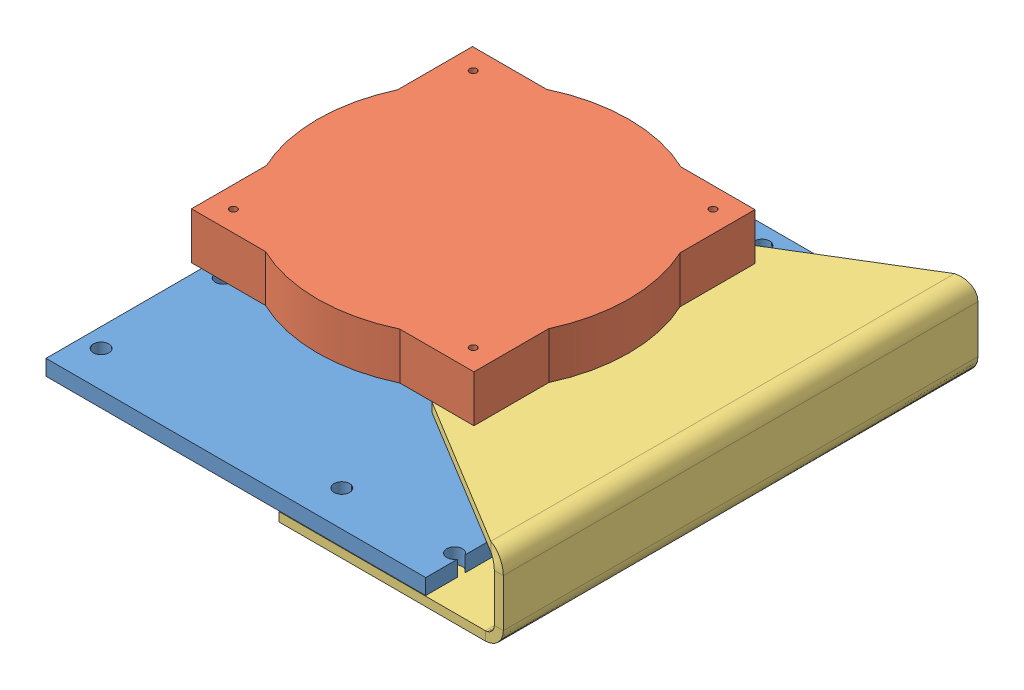
SolidWorks assembly Fan mount, configuration Default. Lengths in mm.
Overall size (293.66 83.88 304.8).
3 component instances, 3 part files, 4 mates.
Components (placement in the parent):
- board blank-1: board blank [Default] at origin size (243.84 10 304.8)
- Fan blank-1: Fan blank [Default] at (0 47.6947 0) size (200 30 200)
- fan mount-1: fan mount [Default] at (-215.0891 -6.3709 79.0417) size (144.07 53.7 304.8)
Mates (geometry in assembly coordinates):
- Coincident2: coordinate: point of board blank-1; point of assembly
- Coincident11: coincident: plane of board blank-1 through (0 0 0) normal (0 0 1); plane of Fan blank-1 through (0 47.6947 0) normal (0 0 1)
- Coincident16: coincident: plane of board blank-1 through (0 0 0) normal (0 0 1); plane of Fan blank-1 through (0 47.6947 0) normal (0 0 1)
- Coincident23: coincident aligned: plane of board blank-1 through (0 0 0) normal (1 0 0); plane of Fan blank-1 through (0 47.6947 0) normal (1 0 0)
